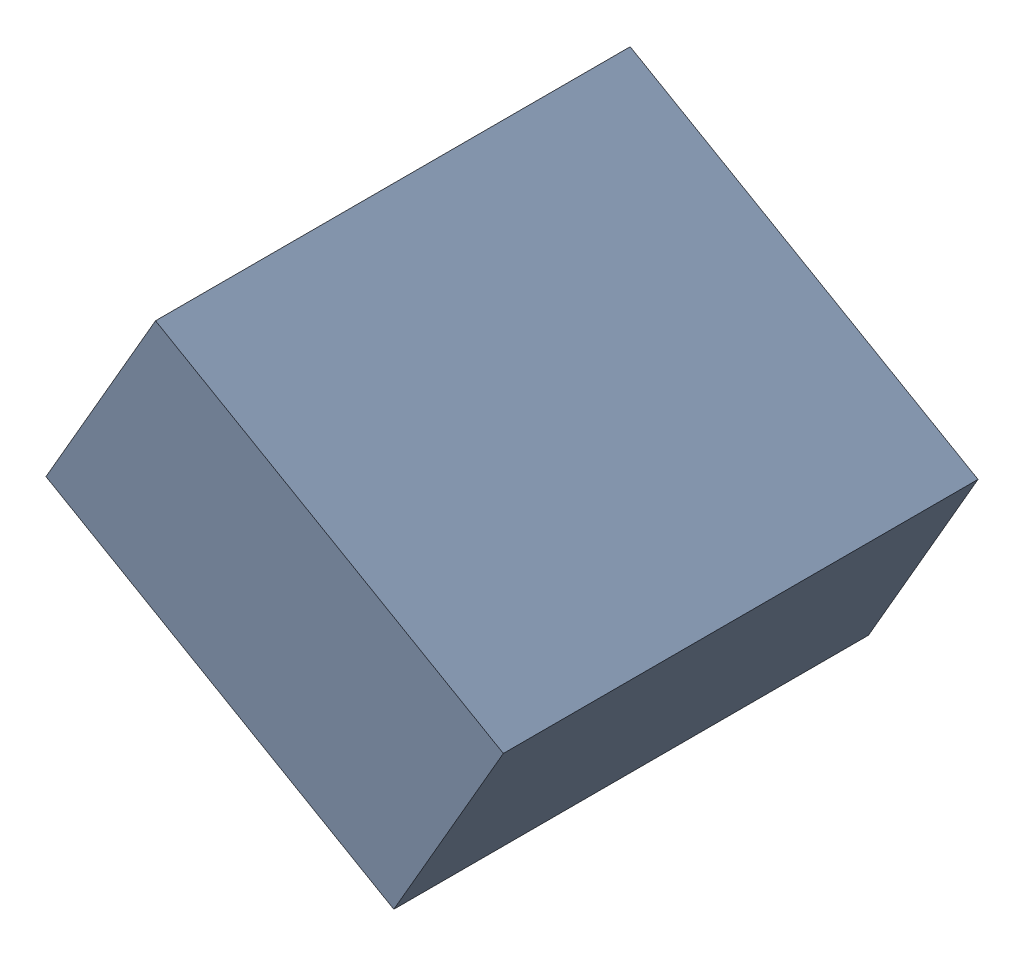
SolidWorks assembly C21_TDA3, configuration Standard. Lengths in mm.
Overall size (1.25 1.07 1.3).
2 component instances, 1 part files, 0 mates.
Components (placement in the parent):
- 885543056-1: 885543056 [Standard] at (44.3524 -22.8708 0) size (1.25 1.07 1.3)
  - Extruded_23-1: Extruded_23 [Standard] at origin size (1.25 1.07 1.3)
